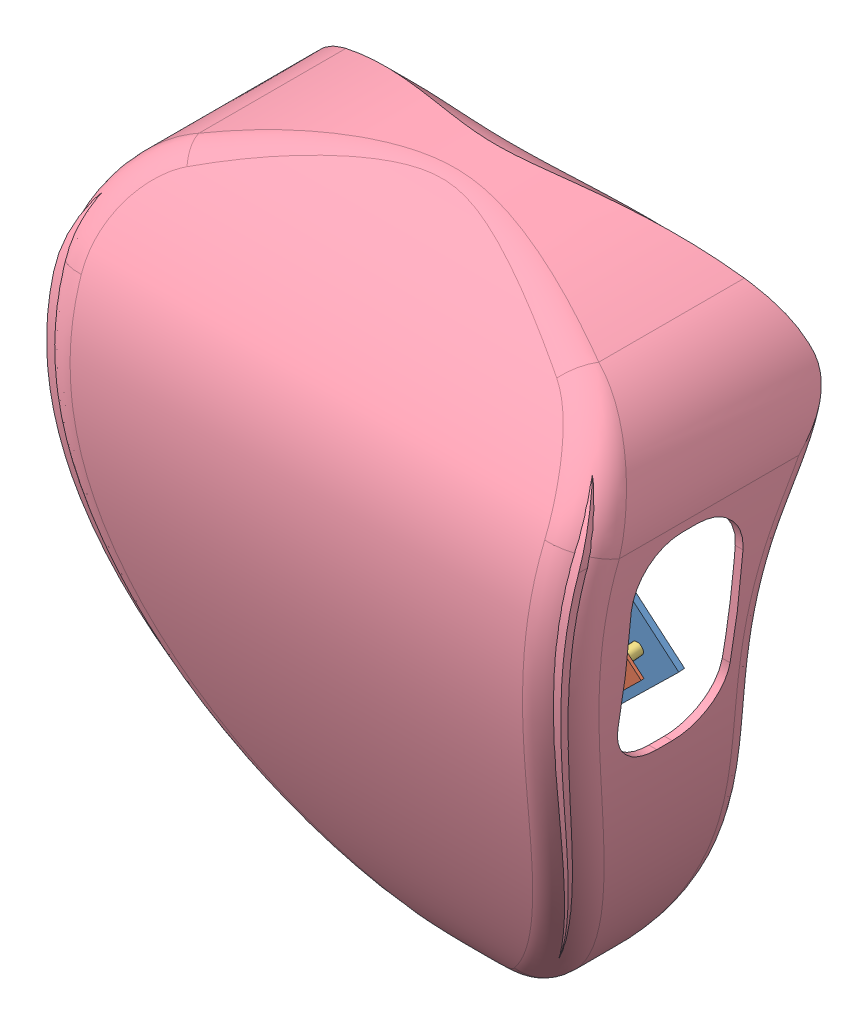
SolidWorks assembly MOchila Wrap, configuration Default. Lengths in mm.
Overall size (321.04 383.6 170.37).
8 component instances, 4 part files, 0 mates.
Components (placement in the parent):
- Jetson H-2: Jetson H [Default] at (189.1373 429.5462 162.1557) x (0.700909 -0.710536 -0.062164) z (-0.713223 -0.698976 -0.052393) size (180 45.5 180)
  - Base-1: Base [Default] at (67.0689 90.6709 139.4266) size (180 3 180)
  - Board-1: Board [Default] at (67.0689 104.6709 139.4266) size (170 31.5 170)
  - Separador-1: Separador [Default] at (-7.9311 93.6709 214.4266) x (0.99477 0 -0.102141) z (0.102141 0 0.99477) size (6 11 6)
  - Separador-2: Separador [Default] at (142.0689 93.6709 64.4266) size (6 11 6)
  - Separador-3: Separador [Default] at (142.0689 93.6709 214.4266) size (6 11 6)
  - Separador-4: Separador [Default] at (-7.9311 93.6709 64.4266) size (6 11 6)
- backpack 2d-1: backpack 2d [Default] at (136.8804 292.7314 174.5447) size (321.04 383.6 170.37)
